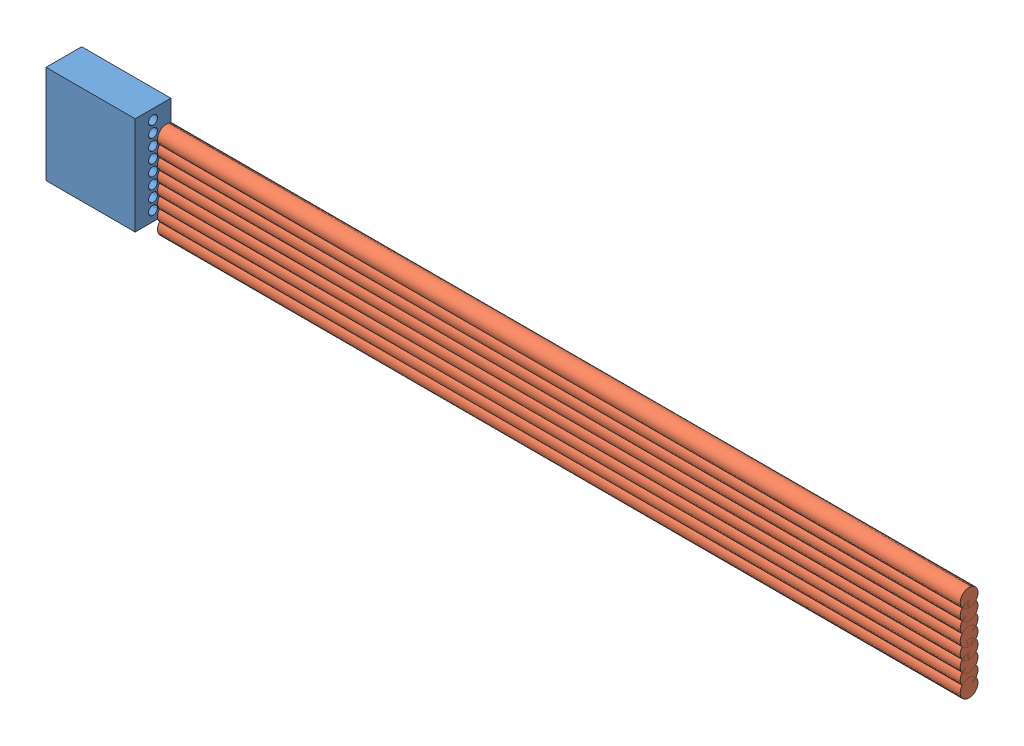
SolidWorks assembly Harness_25-CABLE_REALOP_ONE_ASSEMBLY, configuration AnnotateFlattenedRoute1 - Default. Lengths in mm.
Overall size (101.5 11.5 4).
3 component instances, 3 part files, 2 mates.
Components (placement in the parent):
- 8_PIN-1: 8_PIN [Default] at (-11.5 -9.25 2) x (0 -1 0) z (1 0 0) size (11 4 20)
- Cable^Harness_25-CABLE_REALOP_ONE_ASSEMBLY-1: Cable^Harness_25-CABLE_REALOP_ONE_ASSEMBLY [Default] at origin size (13.37 35.31 29.91) (suppressed, hidden, virtual)
- Flattened_Cable^Harness_25-CABLE_REALOP_ONE_ASSEMBLY-1: Flattened_Cable^Harness_25-CABLE_REALOP_ONE_ASSEMBLY [Default] at origin (virtual)
Mates (geometry in assembly coordinates):
- Coincident991: coincident anti-aligned: plane of X_AND_Y_SOLAR_ARRAYS-2 through (89.5177 -21.2025 126.3251) normal (-1 0 0); plane of 8_PIN-1 through (89.5177 31.0137 258.5133) normal (1 0 0)
- Coincident9921: coincident anti-aligned: plane of 1_PIN-1 through (89.5177 42.7161 253.9035) normal (1 0 0); plane of X_AND_Y_SOLAR_ARRAYS-2 through (89.5177 -21.2025 126.3251) normal (-1 0 0)
